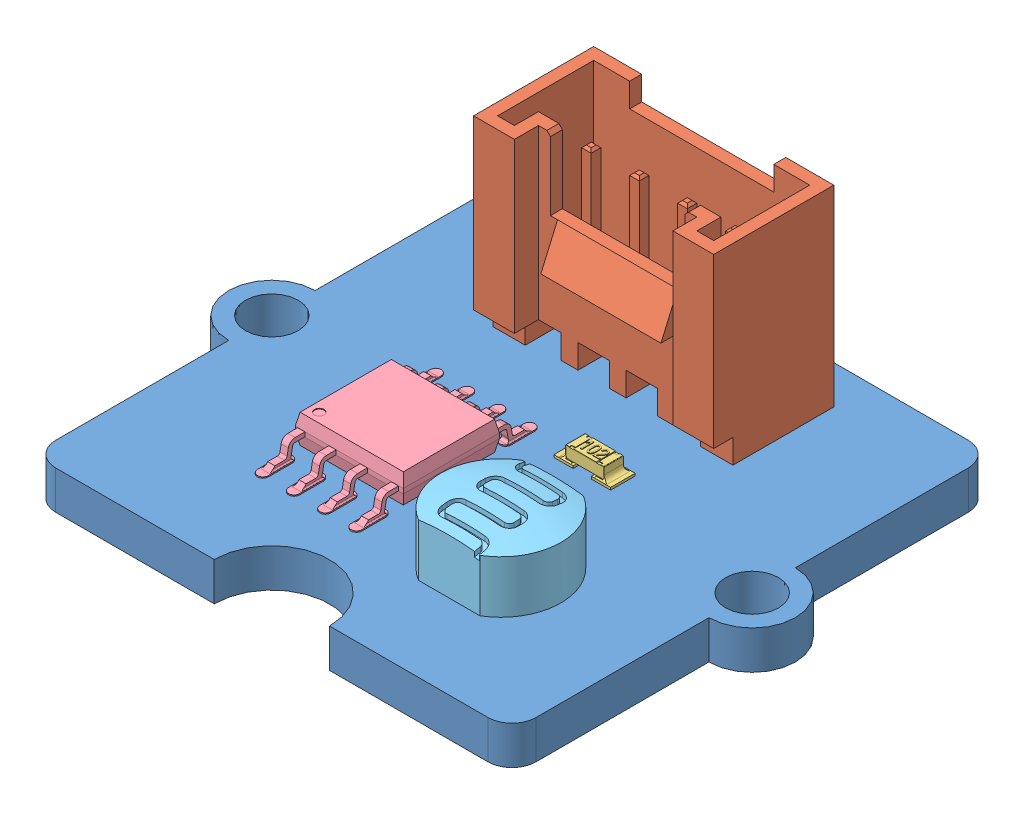
SolidWorks assembly Grove light sensor, configuration Défaut. Lengths in mm.
Overall size (23.6 11 20).
5 component instances, 5 part files, 11 mates.
Components (placement in the parent):
- PCB grove 20x20-1: PCB grove 20x20 [Défaut] at (-2.2687 -8.6505 3.8647) x (0 0 1) z (-1 0 0) size (20 1.6 23.6)
- Connecteur Grove (droit)-1: Connecteur Grove (droit) [Défaut] at (-2.2687 -7.0505 0.4647) size (10 11 5)
- 603 resistor 102-1: 603 resistor 102 [Default] at (1.0464 -5.9085 3.7437) size (2.36 0.62 1.03)
- LM358-1: LM358 [Default] at (-4.7437 -7.0505 6.1647) x (0 0 1) z (-1 0 0) size (7.65 1.3 4.5)
- LDR-1: LDR [Défaut] at (1.6178 -7.0505 8.2147) size (5 5 4.3)
Mates (geometry in assembly coordinates):
- Coïncidente3: coincident anti-aligned: plane of PCB grove 20x20-1 through (-2.2687 -7.0505 3.8647) normal (0 1 0); plane of Connecteur Grove (droit)-1 through (-2.2687 -7.0505 0.4647) normal (0 -1 0)
- Distance2: distance = 1.6 mm aligned: plane of PCB grove 20x20-1 through (-2.2687 -7.0505 -6.1353) normal (0 0 -1); plane of Connecteur Grove (droit)-1 through (-7.2687 0.9495 -4.5353) normal (0 0 -1)
- Distance3: distance = 5 mm aligned: plane of Connecteur Grove (droit)-1 through (2.7313 0.9495 -4.5353) normal (1 0 0); plane of PCB grove 20x20-1 through (7.7313 -7.0505 3.8647) normal (1 0 0)
- Verrouiller1: lock: unknown of ?; unknown of ?
- Coïncidente4: coincident anti-aligned: plane of PCB grove 20x20-1 through (-2.2687 -7.0505 3.8647) normal (0 1 0); plane of LM358-1 through (-2.8437 -7.0505 8.7647) normal (0 -1 0)
- Distance5: distance = 5.3 mm: plane of PCB grove 20x20-1 through (-12.2687 -7.0505 3.8647) normal (-1 0 0); line of LM358-1 through (-6.9687 -7.0505 8.7647) axis (0 0 1)
- Distance6: distance = 5.7 mm aligned: plane of LM358-1 through (-6.9937 -6.9505 8.1647) normal (0 0 1); plane of PCB grove 20x20-1 through (-2.2687 -7.0505 13.8647) normal (0 0 1)
- Verrouiller2: lock: unknown of ?; unknown of ?
- Coïncidente11: coincident anti-aligned: plane of PCB grove 20x20-1 through (-2.2687 -7.0505 3.8647) normal (0 1 0); plane of LDR-1 through (4.1178 -7.0505 8.2147) normal (0 -1 0)
- Distance7: distance = 3.5 mm aligned: plane of LDR-1 through (-2.6147 2.9495 10.3647) normal (0 0 1); plane of PCB grove 20x20-1 through (-2.2687 -7.0505 13.8647) normal (0 0 1)
- Distance9: distance = 4.8378 mm: point of LDR-1; plane of PCB grove 20x20-1 through (7.7313 -7.0505 3.8647) normal (1 0 0)
